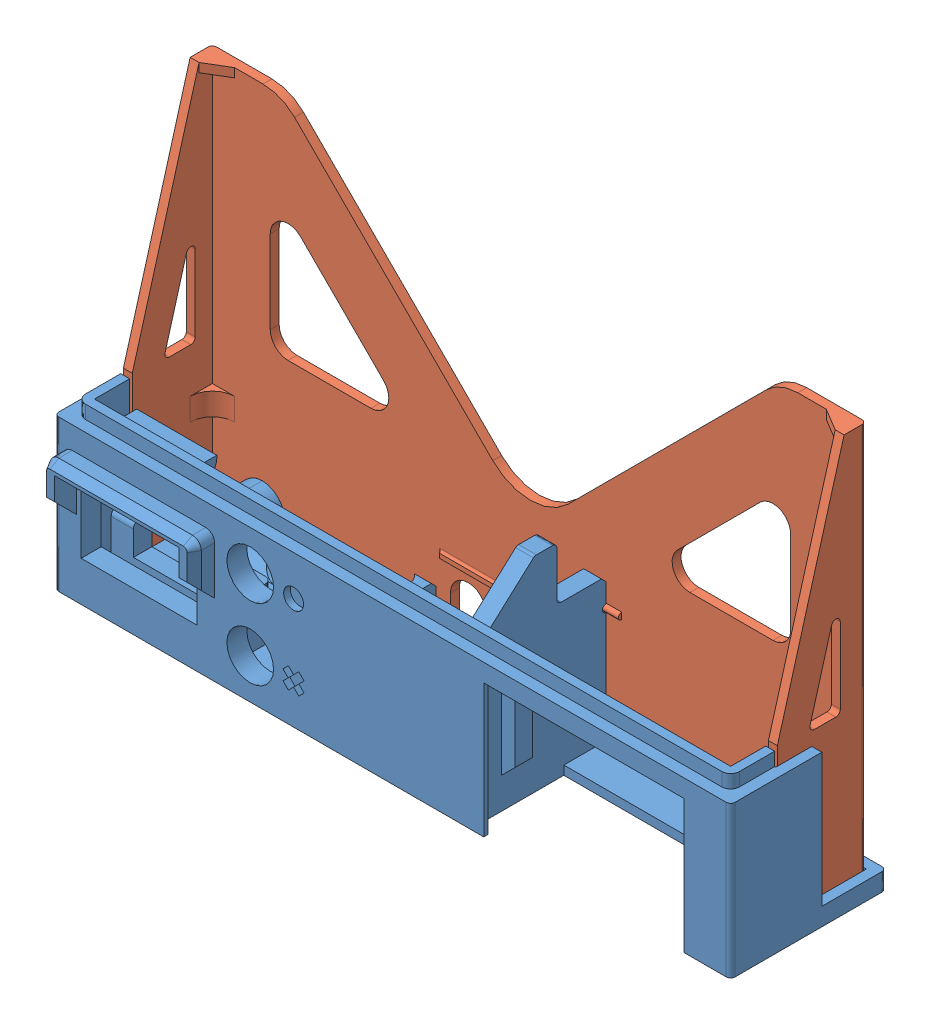
SolidWorks assembly adaptaçãoTampaAntena, configuration Valor predeterminado. Lengths in mm.
Overall size (152 91 40).
2 component instances, 2 part files, 2 mates.
Components (placement in the parent):
- tampa_001-1: tampa_001 [Valor predeterminado] at (-127.3423 -35.0398 17.5) size (152 46 40)
- base_001-1: base_001 [Valor predeterminado] at (-127.1123 251.3078 17.3429) size (147 89 20)
Mates (geometry in assembly coordinates):
- Distância1: distance = 0.02 mm anti-aligned: plane of base_001-1 through (22.3877 55.9602 -15.27) normal (0 0 -1); plane of tampa_001-1 through (22.4077 -1.0398 -15.25) normal (0 0 1)
- Distância2: distance = 0.02 mm anti-aligned: plane of base_001-1 through (22.3877 55.9602 4.73) normal (1 0 0); plane of tampa_001-1 through (22.4077 -1.0398 5.1) normal (-1 0 0)
